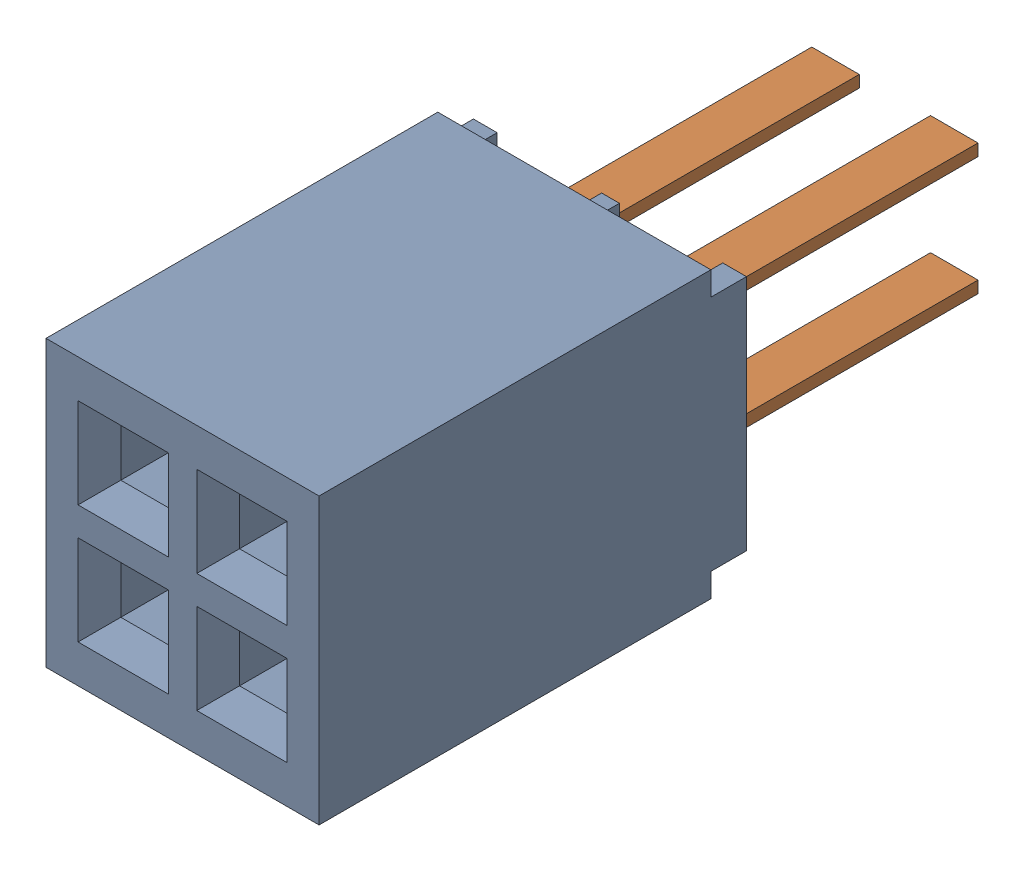
SolidWorks assembly J4, configuration ﾃﾞﾌｫﾙﾄ. Lengths in mm.
Overall size (2.92 3.05 7.62).
3 component instances, 2 part files, 0 mates.
Components (placement in the parent):
- SFMC-102-01-L-D-1: SFMC-102-01-L-D [ﾃﾞﾌｫﾙﾄ] at (62.535 40.97 0) x (-1 0 0) z (0 1 0) size (2.92 7.62 3.05)
  - _SFMC-102-01_socket-1: _SFMC-102-01_socket [ﾃﾞﾌｫﾙﾄ] at origin size (2.92 4.57 3.05)
  - _C-02-01_spins-1: _C-02-01_spins [ﾃﾞﾌｫﾙﾄ] at origin size (1.78 3.81 1.78)
